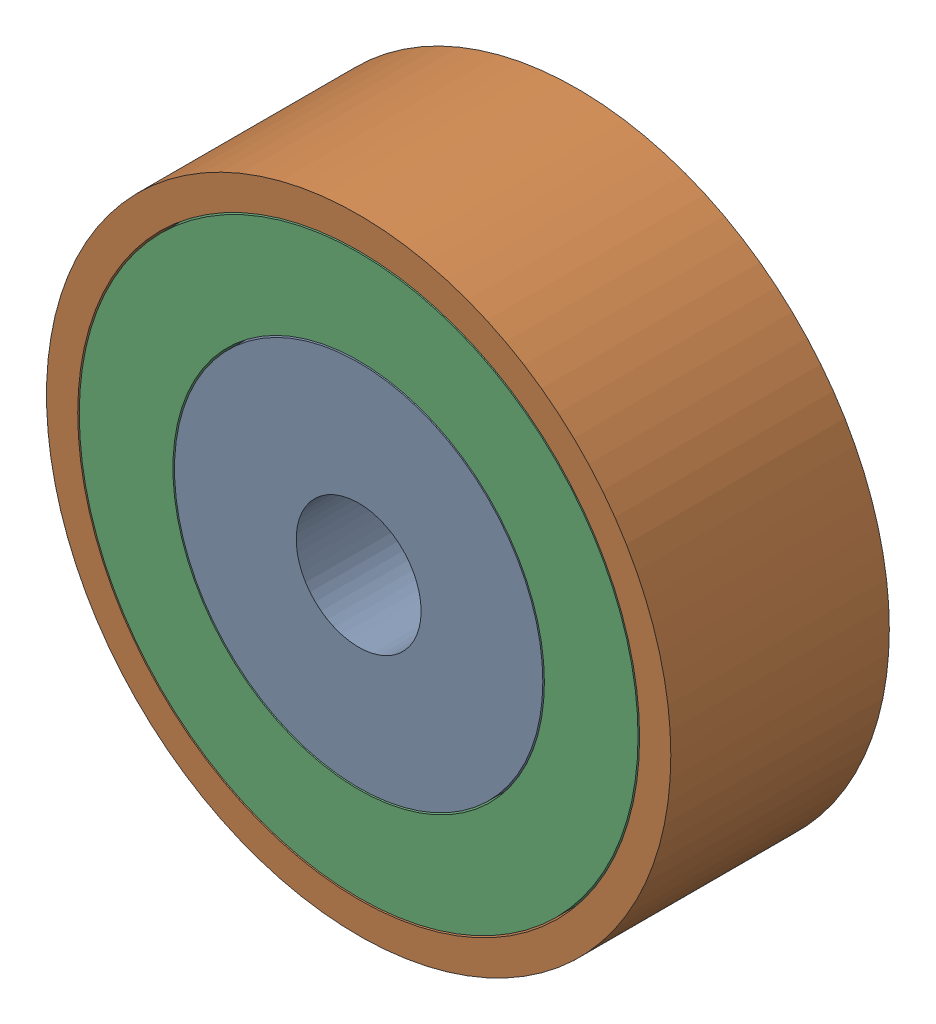
SolidWorks assembly 镜向轴承7, configuration 默认. Lengths in mm.
Overall size (20 20 7).
3 component instances, 3 part files, 4 mates.
Components (placement in the parent):
- 镜向轴承内圈-1: 镜向轴承内圈 [默认] at (-5.0655 0.8032 -6.5) size (11.8 11.8 7)
- 镜向轴承外圈-1: 镜向轴承外圈 [默认] at (-5.0655 0.8032 -6.5) size (20 20 7)
- 镜向轴承中圈-1: 镜向轴承中圈 [默认] at (-5.0655 0.8032 -6.5) size (17.9 17.9 7)
Mates (geometry in assembly coordinates):
- 重合1: coincident: plane of ? through (-5.0655 0.8032 -13.5) normal (0 0 -1); plane of ? through (-5.0655 0.8032 -13.5) normal (0 0 -1)
- 重合2: coincident: plane of ? through (-5.0655 0.8032 -13.5) normal (0 0 -1); plane of ? through (-5.0655 0.8032 -13.5) normal (0 0 -1)
- 同心1: concentric: cylinder of ? through (-5.0655 0.8032 -13.5) axis (0 0 1) radius 9; cylinder of ? through (-5.0655 0.8032 -13.5) axis (0 0 1) radius 8.95
- 同心2: concentric: cylinder of ? through (-5.0655 0.8032 -13.5) axis (0 0 1) radius 5.9; cylinder of ? through (-5.0655 0.8032 -13.5) axis (0 0 1) radius 5.95
